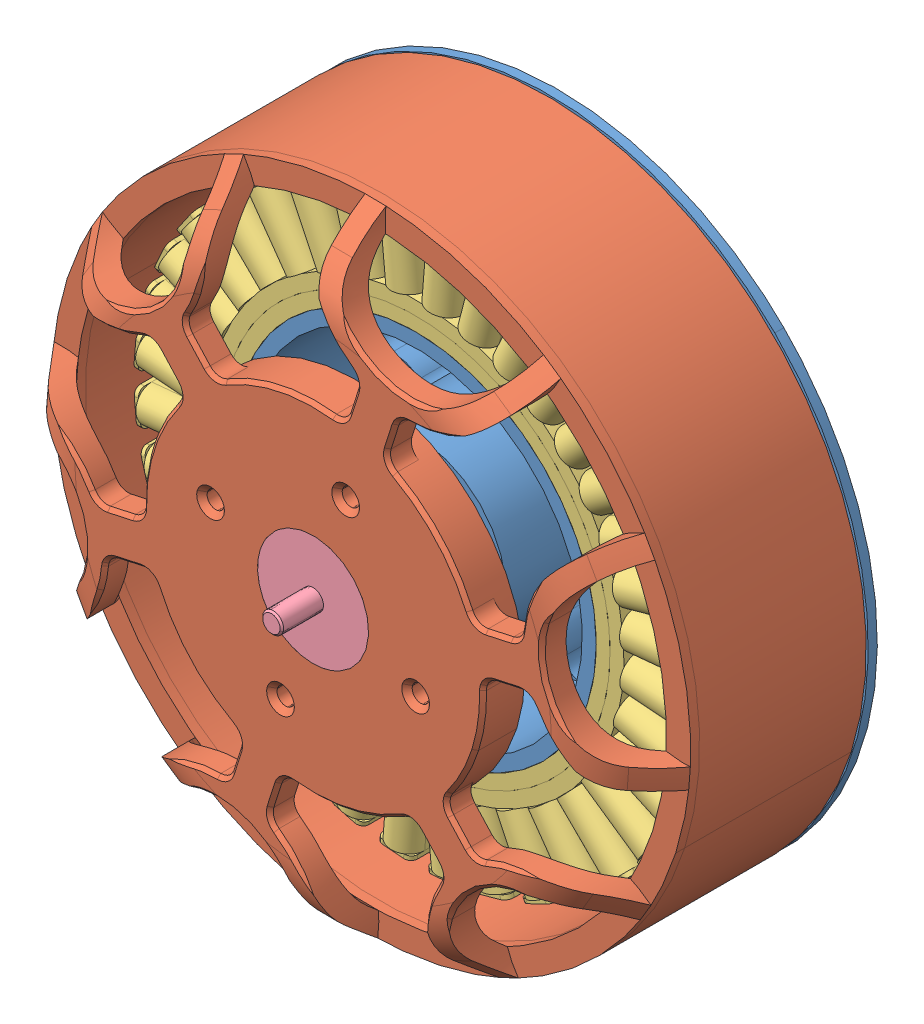
SolidWorks assembly MOTOR 8318, configuration Default. Lengths in mm.
Overall size (130.11 130.11 50.01).
7 component instances, 5 part files, 0 mates.
Components (placement in the parent):
- MOTOR 8318.STEP-1: MOTOR 8318.STEP [Default] at origin size (130.11 130.11 50.01)
  - MOTOR BACK HOUSING REV01.STEP-1: MOTOR BACK HOUSING REV01.STEP [Default] at (0 0 6) x (0.707107 0.707107 0) z (-0.707107 0.707107 0) size (92 25.2 92)
  - MOTOR ROTOR REV01_X8318S.STEP-1: MOTOR ROTOR REV01_X8318S.STEP [Default] at (0 0 6.3) x (-0.302803 -0.953053 0) z (-0.953053 0.302803 0) size (92 33.71 92)
  - MOTOR STATOR REV01.STEP-1: MOTOR STATOR REV01.STEP [Default] at (0 0 7.2) x (-0.996782 0.080159 0) z (0.080159 0.996782 0) size (81.2 19.01 81.2)
  - MOTOR SHAFT REV01_X8318S.STEP-1: MOTOR SHAFT REV01_X8318S.STEP [Default] at (0 0 3.5) x (0.302803 0.953053 0) z (0.953053 -0.302803 0) size (19.64 50.01 18.94)
  - NMB L2112KK BEARING.STEP-1: NMB L2112KK BEARING.STEP [Default] at (0 0 18.7) x (0.90792 -0.419144 0) z (0 0 1) size (21 21 5)
  - NMB L2112KK BEARING.STEP-2: NMB L2112KK BEARING.STEP [Default] at (0 0 3) x (0.990401 -0.138221 0) z (0 0 1) size (21 21 5)
